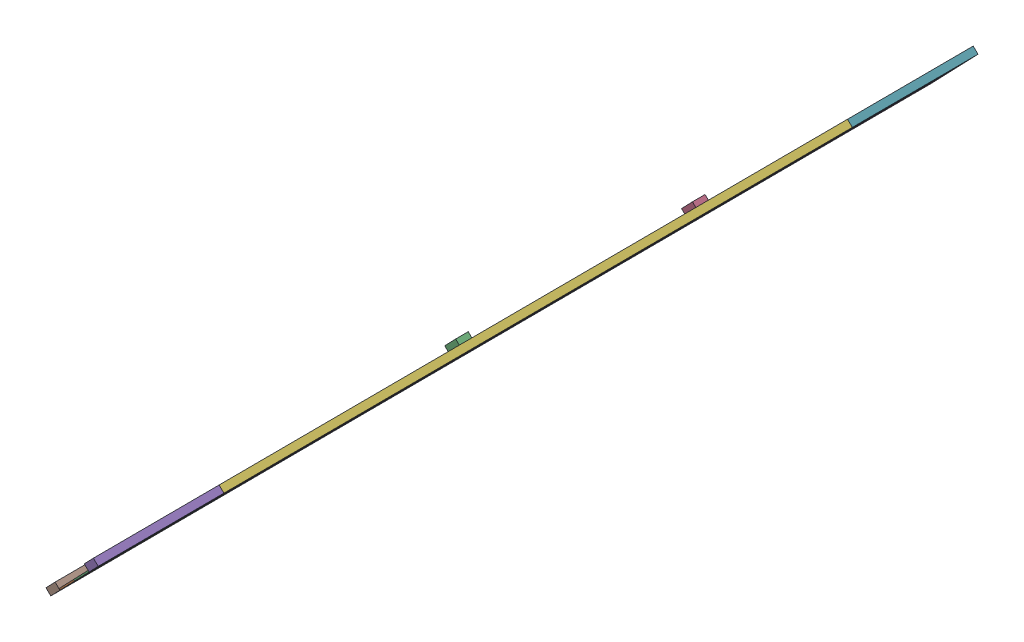
SolidWorks assembly Track_02, configuration Default. Lengths in mm.
Overall size (4967.98 5069.22 14091.02).
160 component instances, 7 part files, 48 mates.
Components (placement in the parent):
- additive_to_track-1: additive_to_track [Default] at (-4229.1798 -351.3174 3673.9855) x (0.662353 0.676347 0.322247) z (-0.225469 -0.230233 0.946656) size (800 25 2000)
- track-1: track [Default] at (-4337.0449 -461.4615 3743.5692) x (-0.662353 -0.676347 -0.322247) z (0.225469 0.230233 -0.946656) size (800 25 10000)
- additive_to_track-2: additive_to_track [Default] at (-6934.8033 -3114.1081 15033.853) x (0.662353 0.676347 0.322247) z (-0.225469 -0.230233 0.946656) size (800 25 2000)
- lane_track_01-1: lane_track_01 [Default] at (-4305.3949 -394.3022 3778.6206) x (0.662353 0.676347 0.322247) z (-0.225469 -0.230233 0.946656) size (50 25 9900)
  - lane-1: lane [Default] at (13.0249 -24.3771 9.6884) size (50 25 100)
  - lane-2: lane [Default] at (13.0249 -24.3771 209.6884) size (50 25 100)
  - lane-3: lane [Default] at (13.0249 -24.3771 409.6884) size (50 25 100)
  - lane-4: lane [Default] at (13.0249 -24.3771 609.6884) size (50 25 100)
  - lane-5: lane [Default] at (13.0249 -24.3771 809.6884) size (50 25 100)
  - lane-6: lane [Default] at (13.0249 -24.3771 1009.6884) size (50 25 100)
  - lane-7: lane [Default] at (13.0249 -24.3771 1209.6884) size (50 25 100)
  - lane-8: lane [Default] at (13.0249 -24.3771 1409.6884) size (50 25 100)
  - lane-9: lane [Default] at (13.0249 -24.3771 1609.6884) size (50 25 100)
  - lane-10: lane [Default] at (13.0249 -24.3771 1809.6884) size (50 25 100)
  - lane-11: lane [Default] at (13.0249 -24.3771 2009.6884) size (50 25 100)
  - lane-12: lane [Default] at (13.0249 -24.3771 2209.6884) size (50 25 100)
  - lane-13: lane [Default] at (13.0249 -24.3771 2409.6884) size (50 25 100)
  - lane-14: lane [Default] at (13.0249 -24.3771 2609.6884) size (50 25 100)
  - lane-15: lane [Default] at (13.0249 -24.3771 2809.6884) size (50 25 100)
  - lane-16: lane [Default] at (13.0249 -24.3771 3009.6884) size (50 25 100)
  - lane-17: lane [Default] at (13.0249 -24.3771 3209.6884) size (50 25 100)
  - lane-18: lane [Default] at (13.0249 -24.3771 3409.6884) size (50 25 100)
  - lane-19: lane [Default] at (13.0249 -24.3771 3609.6884) size (50 25 100)
  - lane-20: lane [Default] at (13.0249 -24.3771 3809.6884) size (50 25 100)
  - lane-21: lane [Default] at (13.0249 -24.3771 4009.6884) size (50 25 100)
  - lane-22: lane [Default] at (13.0249 -24.3771 4209.6884) size (50 25 100)
  - lane-23: lane [Default] at (13.0249 -24.3771 4409.6884) size (50 25 100)
  - lane-24: lane [Default] at (13.0249 -24.3771 4609.6884) size (50 25 100)
  - lane-25: lane [Default] at (13.0249 -24.3771 4809.6884) size (50 25 100)
  - lane-26: lane [Default] at (13.0249 -24.3771 5009.6884) size (50 25 100)
  - lane-27: lane [Default] at (13.0249 -24.3771 5209.6884) size (50 25 100)
  - lane-28: lane [Default] at (13.0249 -24.3771 5409.6884) size (50 25 100)
  - lane-29: lane [Default] at (13.0249 -24.3771 5609.6884) size (50 25 100)
  - lane-30: lane [Default] at (13.0249 -24.3771 5809.6884) size (50 25 100)
  - lane-31: lane [Default] at (13.0249 -24.3771 6009.6884) size (50 25 100)
  - lane-32: lane [Default] at (13.0249 -24.3771 6209.6884) size (50 25 100)
  - lane-33: lane [Default] at (13.0249 -24.3771 6409.6884) size (50 25 100)
  - lane-34: lane [Default] at (13.0249 -24.3771 6609.6884) size (50 25 100)
  - lane-35: lane [Default] at (13.0249 -24.3771 6809.6884) size (50 25 100)
  - lane-36: lane [Default] at (13.0249 -24.3771 7009.6884) size (50 25 100)
  - lane-37: lane [Default] at (13.0249 -24.3771 7209.6884) size (50 25 100)
  - lane-38: lane [Default] at (13.0249 -24.3771 7409.6884) size (50 25 100)
  - lane-39: lane [Default] at (13.0249 -24.3771 7609.6884) size (50 25 100)
  - lane-40: lane [Default] at (13.0249 -24.3771 7809.6884) size (50 25 100)
  - lane-41: lane [Default] at (13.0249 -24.3771 8009.6884) size (50 25 100)
  - lane-42: lane [Default] at (13.0249 -24.3771 8209.6884) size (50 25 100)
  - lane-43: lane [Default] at (13.0249 -24.3771 8409.6884) size (50 25 100)
  - lane-44: lane [Default] at (13.0249 -24.3771 8609.6884) size (50 25 100)
  - lane-45: lane [Default] at (13.0249 -24.3771 8809.6884) size (50 25 100)
  - lane-46: lane [Default] at (13.0249 -24.3771 9009.6884) size (50 25 100)
  - lane-47: lane [Default] at (13.0249 -24.3771 9209.6884) size (50 25 100)
  - lane-48: lane [Default] at (13.0249 -24.3771 9409.6884) size (50 25 100)
  - lane-49: lane [Default] at (13.0249 -24.3771 9609.6884) size (50 25 100)
  - lane-50: lane [Default] at (13.0249 -24.3771 9809.6884) size (50 25 100)
- lane_addetive-1: lane_addetive [Default] at (-3840.8356 56.0354 1861.6407) x (0.662353 0.676347 0.322247) z (-0.225469 -0.230233 0.946656) size (50 25 1900)
  - lane-1: lane [Default] at (18.4792 -7.5587 32.8341) size (50 25 100)
  - lane-2: lane [Default] at (18.4792 -7.5587 232.8341) size (50 25 100)
  - lane-3: lane [Default] at (18.4792 -7.5587 432.8341) size (50 25 100)
  - lane-4: lane [Default] at (18.4792 -7.5587 632.8341) size (50 25 100)
  - lane-5: lane [Default] at (18.4792 -7.5587 832.8341) size (50 25 100)
  - lane-6: lane [Default] at (18.4792 -7.5587 1032.8341) size (50 25 100)
  - lane-7: lane [Default] at (18.4792 -7.5587 1232.8341) size (50 25 100)
  - lane-8: lane [Default] at (18.4792 -7.5587 1432.8341) size (50 25 100)
  - lane-9: lane [Default] at (18.4792 -7.5587 1632.8341) size (50 25 100)
  - lane-10: lane [Default] at (18.4792 -7.5587 1832.8341) size (50 25 100)
- lane_addetive-2: lane_addetive [Default] at (-6546.4591 -2706.7553 13221.5082) x (0.662353 0.676347 0.322247) z (-0.225469 -0.230233 0.946656) size (50 25 1900)
  - lane-1: lane [Default] at (18.4792 -7.5587 32.8341) size (50 25 100)
  - lane-2: lane [Default] at (18.4792 -7.5587 232.8341) size (50 25 100)
  - lane-3: lane [Default] at (18.4792 -7.5587 432.8341) size (50 25 100)
  - lane-4: lane [Default] at (18.4792 -7.5587 632.8341) size (50 25 100)
  - lane-5: lane [Default] at (18.4792 -7.5587 832.8341) size (50 25 100)
  - lane-6: lane [Default] at (18.4792 -7.5587 1032.8341) size (50 25 100)
  - lane-7: lane [Default] at (18.4792 -7.5587 1232.8341) size (50 25 100)
  - lane-8: lane [Default] at (18.4792 -7.5587 1432.8341) size (50 25 100)
  - lane-9: lane [Default] at (18.4792 -7.5587 1632.8341) size (50 25 100)
  - lane-10: lane [Default] at (18.4792 -7.5587 1832.8341) size (50 25 100)
- additive_to_track-3: additive_to_track [Default] at (-7464.6854 -3655.1861 14776.0553) x (0.662353 0.676347 0.322247) z (-0.225469 -0.230233 0.946656) size (800 25 2000)
- lane_track_01-2: lane_track_01 [Default] at (-4835.277 -935.3802 3520.823) x (0.662353 0.676347 0.322247) z (-0.225469 -0.230233 0.946656) size (50 25 9900)
  - lane-1: lane [Default] at (13.0249 -24.3771 9.6884) size (50 25 100)
  - lane-2: lane [Default] at (13.0249 -24.3771 209.6884) size (50 25 100)
  - lane-3: lane [Default] at (13.0249 -24.3771 409.6884) size (50 25 100)
  - lane-4: lane [Default] at (13.0249 -24.3771 609.6884) size (50 25 100)
  - lane-5: lane [Default] at (13.0249 -24.3771 809.6884) size (50 25 100)
  - lane-6: lane [Default] at (13.0249 -24.3771 1009.6884) size (50 25 100)
  - lane-7: lane [Default] at (13.0249 -24.3771 1209.6884) size (50 25 100)
  - lane-8: lane [Default] at (13.0249 -24.3771 1409.6884) size (50 25 100)
  - lane-9: lane [Default] at (13.0249 -24.3771 1609.6884) size (50 25 100)
  - lane-10: lane [Default] at (13.0249 -24.3771 1809.6884) size (50 25 100)
  - lane-11: lane [Default] at (13.0249 -24.3771 2009.6884) size (50 25 100)
  - lane-12: lane [Default] at (13.0249 -24.3771 2209.6884) size (50 25 100)
  - lane-13: lane [Default] at (13.0249 -24.3771 2409.6884) size (50 25 100)
  - lane-14: lane [Default] at (13.0249 -24.3771 2609.6884) size (50 25 100)
  - lane-15: lane [Default] at (13.0249 -24.3771 2809.6884) size (50 25 100)
  - lane-16: lane [Default] at (13.0249 -24.3771 3009.6884) size (50 25 100)
  - lane-17: lane [Default] at (13.0249 -24.3771 3209.6884) size (50 25 100)
  - lane-18: lane [Default] at (13.0249 -24.3771 3409.6884) size (50 25 100)
  - lane-19: lane [Default] at (13.0249 -24.3771 3609.6884) size (50 25 100)
  - lane-20: lane [Default] at (13.0249 -24.3771 3809.6884) size (50 25 100)
  - lane-21: lane [Default] at (13.0249 -24.3771 4009.6884) size (50 25 100)
  - lane-22: lane [Default] at (13.0249 -24.3771 4209.6884) size (50 25 100)
  - lane-23: lane [Default] at (13.0249 -24.3771 4409.6884) size (50 25 100)
  - lane-24: lane [Default] at (13.0249 -24.3771 4609.6884) size (50 25 100)
  - lane-25: lane [Default] at (13.0249 -24.3771 4809.6884) size (50 25 100)
  - lane-26: lane [Default] at (13.0249 -24.3771 5009.6884) size (50 25 100)
  - lane-27: lane [Default] at (13.0249 -24.3771 5209.6884) size (50 25 100)
  - lane-28: lane [Default] at (13.0249 -24.3771 5409.6884) size (50 25 100)
  - lane-29: lane [Default] at (13.0249 -24.3771 5609.6884) size (50 25 100)
  - lane-30: lane [Default] at (13.0249 -24.3771 5809.6884) size (50 25 100)
  - lane-31: lane [Default] at (13.0249 -24.3771 6009.6884) size (50 25 100)
  - lane-32: lane [Default] at (13.0249 -24.3771 6209.6884) size (50 25 100)
  - lane-33: lane [Default] at (13.0249 -24.3771 6409.6884) size (50 25 100)
  - lane-34: lane [Default] at (13.0249 -24.3771 6609.6884) size (50 25 100)
  - lane-35: lane [Default] at (13.0249 -24.3771 6809.6884) size (50 25 100)
  - lane-36: lane [Default] at (13.0249 -24.3771 7009.6884) size (50 25 100)
  - lane-37: lane [Default] at (13.0249 -24.3771 7209.6884) size (50 25 100)
  - lane-38: lane [Default] at (13.0249 -24.3771 7409.6884) size (50 25 100)
  - lane-39: lane [Default] at (13.0249 -24.3771 7609.6884) size (50 25 100)
  - lane-40: lane [Default] at (13.0249 -24.3771 7809.6884) size (50 25 100)
  - lane-41: lane [Default] at (13.0249 -24.3771 8009.6884) size (50 25 100)
  - lane-42: lane [Default] at (13.0249 -24.3771 8209.6884) size (50 25 100)
  - lane-43: lane [Default] at (13.0249 -24.3771 8409.6884) size (50 25 100)
  - lane-44: lane [Default] at (13.0249 -24.3771 8609.6884) size (50 25 100)
  - lane-45: lane [Default] at (13.0249 -24.3771 8809.6884) size (50 25 100)
  - lane-46: lane [Default] at (13.0249 -24.3771 9009.6884) size (50 25 100)
  - lane-47: lane [Default] at (13.0249 -24.3771 9209.6884) size (50 25 100)
  - lane-48: lane [Default] at (13.0249 -24.3771 9409.6884) size (50 25 100)
  - lane-49: lane [Default] at (13.0249 -24.3771 9609.6884) size (50 25 100)
  - lane-50: lane [Default] at (13.0249 -24.3771 9809.6884) size (50 25 100)
- track-2: track [Default] at (-4866.927 -1002.5395 3485.7716) x (-0.662353 -0.676347 -0.322247) z (0.225469 0.230233 -0.946656) size (800 25 10000)
- lane_addetive-3: lane_addetive [Default] at (-4370.7177 -485.0426 1603.8431) x (0.662353 0.676347 0.322247) z (-0.225469 -0.230233 0.946656) size (50 25 1900)
  - lane-1: lane [Default] at (18.4792 -7.5587 32.8341) size (50 25 100)
  - lane-2: lane [Default] at (18.4792 -7.5587 232.8341) size (50 25 100)
  - lane-3: lane [Default] at (18.4792 -7.5587 432.8341) size (50 25 100)
  - lane-4: lane [Default] at (18.4792 -7.5587 632.8341) size (50 25 100)
  - lane-5: lane [Default] at (18.4792 -7.5587 832.8341) size (50 25 100)
  - lane-6: lane [Default] at (18.4792 -7.5587 1032.8341) size (50 25 100)
  - lane-7: lane [Default] at (18.4792 -7.5587 1232.8341) size (50 25 100)
  - lane-8: lane [Default] at (18.4792 -7.5587 1432.8341) size (50 25 100)
  - lane-9: lane [Default] at (18.4792 -7.5587 1632.8341) size (50 25 100)
  - lane-10: lane [Default] at (18.4792 -7.5587 1832.8341) size (50 25 100)
- additive_to_track-4: additive_to_track [Default] at (-4759.0619 -892.3953 3416.1879) x (0.662353 0.676347 0.322247) z (-0.225469 -0.230233 0.946656) size (800 25 2000)
- lane_addetive-4: lane_addetive [Default] at (-7076.3412 -3247.8333 12963.7106) x (0.662353 0.676347 0.322247) z (-0.225469 -0.230233 0.946656) size (50 25 1900)
  - lane-1: lane [Default] at (18.4792 -7.5587 32.8341) size (50 25 100)
  - lane-2: lane [Default] at (18.4792 -7.5587 232.8341) size (50 25 100)
  - lane-3: lane [Default] at (18.4792 -7.5587 432.8341) size (50 25 100)
  - lane-4: lane [Default] at (18.4792 -7.5587 632.8341) size (50 25 100)
  - lane-5: lane [Default] at (18.4792 -7.5587 832.8341) size (50 25 100)
  - lane-6: lane [Default] at (18.4792 -7.5587 1032.8341) size (50 25 100)
  - lane-7: lane [Default] at (18.4792 -7.5587 1232.8341) size (50 25 100)
  - lane-8: lane [Default] at (18.4792 -7.5587 1432.8341) size (50 25 100)
  - lane-9: lane [Default] at (18.4792 -7.5587 1632.8341) size (50 25 100)
  - lane-10: lane [Default] at (18.4792 -7.5587 1832.8341) size (50 25 100)
- obstacle_1-1: obstacle_1 [Default] at (-5664.3948 -1781.1263 9317.9215) x (0.225469 0.230233 -0.946656) z (0.662353 0.676347 0.322247) size (200 200 600)
- obstacle_2-2: obstacle_2 [Default] at (-5093.6966 -1198.3697 5370.1755) x (0.225469 0.230233 -0.946656) z (0.662353 0.676347 0.322247) size (200 200 600)
- add_sidewalk-1: add_sidewalk [Default] at (-6504.2902 -2674.4986 14160.0626) x (0.662353 0.676347 0.322247) z (-0.225469 -0.230233 0.946656) size (500 125 2000)
- sidewalk-1: sidewalk [Default] at (-6244.6829 -2409.4061 13265.3484) x (0.662353 0.676347 0.322247) z (-0.225469 -0.230233 0.946656) size (500 125 10000)
- add_sidewalk-2: add_sidewalk [Default] at (-3448.4492 445.9094 3136.6633) x (-0.662353 -0.676347 -0.322247) z (0.225469 0.230233 -0.946656) size (500 125 2000)
- add_sidewalk-3: add_sidewalk [Default] at (-7895.2307 -4094.8283 13483.3439) x (0.662353 0.676347 0.322247) z (-0.225469 -0.230233 0.946656) size (500 125 2000)
- sidewalk-2: sidewalk [Default] at (-7635.6234 -3829.7358 12588.6297) x (0.662353 0.676347 0.322247) z (-0.225469 -0.230233 0.946656) size (500 125 10000)
- add_sidewalk-4: add_sidewalk [Default] at (-4839.3896 -974.4203 2459.9446) x (-0.662353 -0.676347 -0.322247) z (0.225469 0.230233 -0.946656) size (500 125 2000)
Mates (geometry in assembly coordinates):
- Coincident1: coincident anti-aligned: plane of additive_to_track-1 through (-4259.0256 -346.0629 3724.3026) normal (-0.225469 -0.230233 0.946656); plane of track-1 through (-4340.8376 -429.6035 3684.4995) normal (0.225469 0.230233 -0.946656)
- Coincident2: coincident aligned: plane of additive_to_track-1 through (-4020.492 -102.4893 3784.206) normal (0.662353 0.676347 0.322247); plane of track-1 through (-4046.5451 -129.0929 3893.5928) normal (0.662353 0.676347 0.322247)
- Coincident3: coincident aligned: plane of additive_to_track-1 through (-4247.0413 -333.8254 3673.9855) normal (-0.71446 0.699676 0); plane of track-1 through (-4354.9064 -443.9696 3743.5692) normal (-0.71446 0.699676 0)
- Coincident5: coincident anti-aligned: plane of track-1 through (-6595.5238 -2731.9291 13151.0557) normal (-0.225469 -0.230233 0.946656); plane of additive_to_track-2 through (-6513.7118 -2648.3885 13190.8588) normal (0.225469 0.230233 -0.946656)
- Coincident6: coincident aligned: plane of track-1 through (-4354.9064 -443.9696 3743.5692) normal (-0.71446 0.699676 0); plane of additive_to_track-2 through (-6952.6648 -3096.6162 15033.853) normal (-0.71446 0.699676 0)
- Coincident7: coincident aligned: plane of track-1 through (-4046.5451 -129.0929 3893.5928) normal (0.662353 0.676347 0.322247); plane of additive_to_track-2 through (-6726.1155 -2865.2801 15144.0735) normal (0.662353 0.676347 0.322247)
- Coincident8: coincident aligned: plane of track-1 through (-4354.9064 -443.9696 3743.5692) normal (-0.71446 0.699676 0); plane of lane_track_01-1/lane-20 through (-5156.178 -1262.1713 7389.2808) normal (-0.71446 0.699676 0)
- Coincident9: coincident anti-aligned: plane of track-1 through (-6572.9769 -2708.9059 13056.3901) normal (0.225469 0.230233 -0.946656); plane of lane_track_01-1/lane-50 through (-6546.1155 -2681.4768 13069.4588) normal (-0.225469 -0.230233 0.946656)
- Coincident10: coincident anti-aligned: plane of track-1 through (-4294.9273 -382.7232 3772.7502) normal (-0.662353 -0.676347 -0.322247); plane of lane_track_01-1/lane-50 through (-6490.451 -2624.6362 12990.9056) normal (0.662353 0.676347 0.322247)
- Coincident11: coincident aligned: plane of additive_to_track-2 through (-6952.6648 -3096.6162 15033.853) normal (-0.71446 0.699676 0); plane of lane_addetive-2/lane-6 through (-6779.5521 -2919.8457 14205.2013) normal (-0.71446 0.699676 0)
- Coincident12: coincident anti-aligned: plane of additive_to_track-2 through (-6942.1022 -3085.8304 14989.5045) normal (0.225469 0.230233 -0.946656); plane of lane_addetive-2/lane-10 through (-6997.0527 -3141.9419 14962.77) normal (-0.225469 -0.230233 0.946656)
- Coincident13: coincident anti-aligned: plane of additive_to_track-2 through (-7007.6153 -3152.7278 15007.1185) normal (0.662353 0.676347 0.322247); plane of lane_addetive-2/lane-10 through (-6974.5058 -3118.9187 14868.1044) normal (-0.662353 -0.676347 -0.322247)
- Coincident14: coincident aligned: plane of additive_to_track-1 through (-4247.0413 -333.8254 3673.9855) normal (-0.71446 0.699676 0); plane of lane_addetive-1/lane-4 through (-3983.7412 -64.962 2466.6716) normal (-0.71446 0.699676 0)
- Coincident15: coincident anti-aligned: plane of additive_to_track-1 through (-4236.4787 -323.0396 3629.637) normal (0.225469 0.230233 -0.946656); plane of lane_addetive-1/lane-10 through (-4291.4292 -379.1512 3602.9025) normal (-0.225469 -0.230233 0.946656)
- Coincident16: coincident anti-aligned: plane of additive_to_track-1 through (-4301.9919 -389.937 3647.251) normal (0.662353 0.676347 0.322247); plane of lane_addetive-1/lane-10 through (-4268.8824 -356.1279 3508.237) normal (-0.662353 -0.676347 -0.322247)
- Coincident17: coincident anti-aligned: plane of track-2 through (-4857.927 -957.6186 3498.8402) normal (0.662353 0.676347 0.322247); plane of lane_track_01-2/lane-50 through (-7053.4507 -3199.5315 12716.9956) normal (-0.662353 -0.676347 -0.322247)
- Coincident18: coincident anti-aligned: plane of lane_track_01-2/lane-50 through (-7075.9975 -3222.5548 12811.6612) normal (-0.225469 -0.230233 0.946656); plane of track-2 through (-7102.859 -3249.9838 12798.5925) normal (0.225469 0.230233 -0.946656)
- Coincident19: coincident anti-aligned: plane of additive_to_track-3 through (-7537.4974 -3693.8057 14749.3209) normal (0.662353 0.676347 0.322247); plane of lane_addetive-4/lane-10 through (-7504.3879 -3659.9967 14610.3068) normal (-0.662353 -0.676347 -0.322247)
- Coincident20: coincident aligned: plane of track-2 through (-4884.7885 -985.0476 3485.7716) normal (-0.71446 0.699676 0); plane of additive_to_track-4 through (-4776.9234 -874.9034 3416.1879) normal (-0.71446 0.699676 0)
- Coincident21: coincident anti-aligned: plane of track-2 through (-4870.7196 -970.6815 3426.7019) normal (0.225469 0.230233 -0.946656); plane of additive_to_track-4 through (-4788.9076 -887.1409 3466.505) normal (-0.225469 -0.230233 0.946656)
- Coincident22: coincident anti-aligned: plane of additive_to_track-3 through (-7043.5939 -3189.4665 12933.0612) normal (0.225469 0.230233 -0.946656); plane of track-2 through (-7125.4059 -3273.0071 12893.2581) normal (-0.225469 -0.230233 0.946656)
- Coincident23: coincident aligned: plane of additive_to_track-3 through (-7482.5469 -3637.6942 14776.0553) normal (-0.71446 0.699676 0); plane of track-2 through (-4884.7885 -985.0476 3485.7716) normal (-0.71446 0.699676 0)
- Coincident24: coincident aligned: plane of track-2 through (-4576.4272 -670.1709 3635.7952) normal (0.662353 0.676347 0.322247); plane of additive_to_track-4 through (-4550.3741 -643.5673 3526.4084) normal (0.662353 0.676347 0.322247)
- Coincident25: coincident aligned: plane of additive_to_track-3 through (-7255.9976 -3406.3581 14886.2759) normal (0.662353 0.676347 0.322247); plane of track-2 through (-4576.4272 -670.1709 3635.7952) normal (0.662353 0.676347 0.322247)
- Coincident26: coincident aligned: plane of lane_track_01-2/lane-20 through (-5686.0601 -1803.2493 7131.4832) normal (-0.71446 0.699676 0); plane of track-2 through (-4884.7885 -985.0476 3485.7716) normal (-0.71446 0.699676 0)
- Coincident27: coincident aligned: plane of additive_to_track-3 through (-7482.5469 -3637.6942 14776.0553) normal (-0.71446 0.699676 0); plane of lane_addetive-4/lane-6 through (-7309.4342 -3460.9237 13947.4037) normal (-0.71446 0.699676 0)
- Coincident28: coincident anti-aligned: plane of additive_to_track-3 through (-7471.9843 -3626.9083 14731.7069) normal (0.225469 0.230233 -0.946656); plane of lane_addetive-4/lane-10 through (-7526.9348 -3683.0199 14704.9724) normal (-0.225469 -0.230233 0.946656)
- Coincident29: coincident aligned: plane of lane_addetive-3/lane-4 through (-4513.6232 -606.04 2208.874) normal (-0.71446 0.699676 0); plane of additive_to_track-4 through (-4776.9234 -874.9034 3416.1879) normal (-0.71446 0.699676 0)
- Coincident30: coincident anti-aligned: plane of lane_addetive-3/lane-10 through (-4821.3113 -920.2292 3345.1049) normal (-0.225469 -0.230233 0.946656); plane of additive_to_track-4 through (-4766.3608 -864.1176 3371.8394) normal (0.225469 0.230233 -0.946656)
- Coincident31: coincident anti-aligned: plane of lane_addetive-3/lane-10 through (-4798.7644 -897.2059 3250.4394) normal (-0.662353 -0.676347 -0.322247); plane of additive_to_track-4 through (-4831.8739 -931.015 3389.4534) normal (0.662353 0.676347 0.322247)
- Coincident32: coincident aligned: plane of track-1 through (-4354.9064 -443.9696 3743.5692) normal (-0.71446 0.699676 0); plane of additive_to_track-4 through (-4776.9234 -874.9034 3416.1879) normal (-0.71446 0.699676 0)
- Coincident33: coincident aligned: plane of additive_to_track-1 through (-3808.0883 114.4022 1830.9913) normal (0.225469 0.230233 -0.946656); plane of additive_to_track-4 through (-4337.9704 -426.6757 1573.1937) normal (0.225469 0.230233 -0.946656)
- Coincident34: coincident anti-aligned: plane of additive_to_track-1 through (-4550.3741 -643.5673 3526.4084) normal (-0.662353 -0.676347 -0.322247); plane of additive_to_track-4 through (-4550.3741 -643.5673 3526.4084) normal (0.662353 0.676347 0.322247)
- Coincident37: coincident anti-aligned: plane of track-1 through (-4354.9064 -443.9696 3743.5692) normal (-0.71446 0.699676 0); plane of obstacle_1-1 through (-5664.3948 -1781.1263 9317.9215) normal (0.71446 -0.699676 0)
- Distance3: distance = 4000 mm aligned: plane of obstacle_1-1 through (-5991.8268 -1829.6301 9288.8839) normal (-0.225469 -0.230233 0.946656); plane of track-1 through (-6595.5238 -2731.9291 13151.0557) normal (-0.225469 -0.230233 0.946656)
- Distance4: distance = 100 mm aligned: plane of obstacle_1-1 through (-5594.4152 -1423.8216 9482.2321) normal (0.662353 0.676347 0.322247); plane of track-1 through (-4046.5451 -129.0929 3893.5928) normal (0.662353 0.676347 0.322247)
- Coincident40: coincident anti-aligned: plane of track-2 through (-4884.7885 -985.0476 3485.7716) normal (-0.71446 0.699676 0); plane of obstacle_2-2 through (-5093.6966 -1198.3697 5370.1755) normal (0.71446 -0.699676 0)
- Distance5: distance = 8000 mm aligned: plane of obstacle_2-2 through (-5619.8343 -1449.7778 5244.4638) normal (-0.225469 -0.230233 0.946656); plane of track-2 through (-7125.4059 -3273.0071 12893.2581) normal (-0.225469 -0.230233 0.946656)
- Distance6: distance = 100 mm aligned: plane of obstacle_2-2 through (-5619.8343 -1449.7778 5244.4638) normal (-0.662353 -0.676347 -0.322247); plane of track-2 through (-5106.3092 -1211.2489 3377.9976) normal (-0.662353 -0.676347 -0.322247)
- Coincident41: coincident aligned: plane of additive_to_track-2 through (-6964.649 -3108.8536 15084.17) normal (-0.225469 -0.230233 0.946656); plane of add_sidewalk-1 through (-6809.5457 -2807.5499 15194.3905) normal (-0.225469 -0.230233 0.946656)
- Coincident42: coincident anti-aligned: plane of additive_to_track-2 through (-6726.1155 -2865.2801 15144.0735) normal (0.662353 0.676347 0.322247); plane of add_sidewalk-1 through (-6358.6085 -2347.0847 13301.0793) normal (-0.662353 -0.676347 -0.322247)
- Coincident43: coincident aligned: plane of additive_to_track-2 through (-6934.8033 -3114.1081 15033.853) normal (0.71446 -0.699676 0); plane of add_sidewalk-1 through (-6504.2902 -2674.4986 14160.0626) normal (0.71446 -0.699676 0)
- Coincident44: coincident anti-aligned: plane of track-1 through (-4046.5451 -129.0929 3893.5928) normal (0.662353 0.676347 0.322247); plane of sidewalk-1 through (-4103.9222 -44.7591 3834.5231) normal (-0.662353 -0.676347 -0.322247)
- Coincident45: coincident anti-aligned: plane of add_sidewalk-1 through (-6358.6085 -2347.0847 13301.0793) normal (0.225469 0.230233 -0.946656); plane of sidewalk-1 through (-6358.6085 -2347.0847 13301.0793) normal (-0.225469 -0.230233 0.946656)
- Coincident46: coincident aligned: plane of track-1 through (-4337.0449 -461.4615 3743.5692) normal (0.71446 -0.699676 0); plane of sidewalk-1 through (-6244.6829 -2409.4061 13265.3484) normal (0.71446 -0.699676 0)
- Coincident47: coincident anti-aligned: plane of additive_to_track-1 through (-4020.492 -102.4893 3784.206) normal (0.662353 0.676347 0.322247); plane of add_sidewalk-2 through (-4103.9222 -44.7591 3834.5231) normal (-0.662353 -0.676347 -0.322247)
- Coincident48: coincident aligned: plane of additive_to_track-1 through (-3808.0883 114.4022 1830.9913) normal (0.225469 0.230233 -0.946656); plane of add_sidewalk-2 through (-3321.8087 753.8797 2102.3353) normal (0.225469 0.230233 -0.946656)
- Coincident49: coincident aligned: plane of additive_to_track-1 through (-4229.1798 -351.3174 3673.9855) normal (0.71446 -0.699676 0); plane of add_sidewalk-2 through (-3448.4492 445.9094 3136.6633) normal (0.71446 -0.699676 0)
